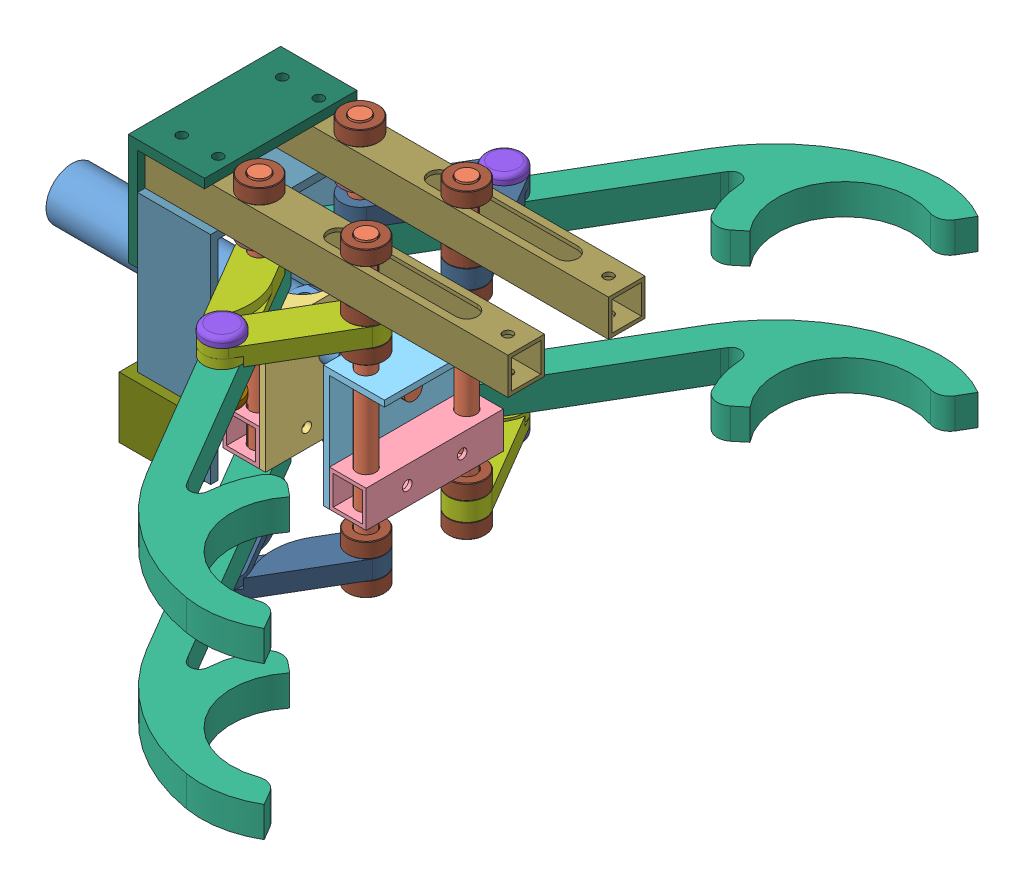
SolidWorks assembly hand_0302ue, configuration ﾃﾞﾌｫﾙﾄ. Lengths in mm.
Overall size (180.12 100 276.7).
52 component instances, 16 part files, 119 mates.
Components (placement in the parent):
- エアシリンダ_可動40-1: エアシリンダ_可動40 [ﾃﾞﾌｫﾙﾄ] at (65.512 -3.3304 50.561) x (1 0 0) z (0 1 0) size (112 17 17) (flexible)
  - ボディ_40-1: ボディ_40 [ﾃﾞﾌｫﾙﾄ] at (-67.4414 2.0168 92) size (92 17 17)
  - 軸_40-1: 軸_40 [ﾃﾞﾌｫﾙﾄ] at (-55.4414 2.0168 92) x (0 0.456107 -0.889925) z (1 0 0) size (6 6 100)
- l字-1: l字 [ﾃﾞﾌｫﾙﾄ] at (82.0707 63.6696 26.0442) x (0 0 1) z (-1 0 0) size (45 40 20)
- 偽l字-1: 偽l字 [ﾃﾞﾌｫﾙﾄ] at (82.0707 63.6696 71.0442) x (0 0 -1) z (1 0 0) size (45 12 12)
- l字改-1: l字改 [ﾃﾞﾌｫﾙﾄ] at (105.0707 63.6696 71.0442) x (0 0 -1) z (1 0 0) size (45 40 20)
- 偽l字-2: 偽l字 [ﾃﾞﾌｫﾙﾄ] at (117.0707 63.6696 71.0442) x (0 0 -1) z (1 0 0) size (45 12 12)
- 稲つかみ機構手 - コピー-1: 稲つかみ機構手 - コピー [ﾃﾞﾌｫﾙﾄ] at (114.8776 40.6696 140.8336) x (0.861801 0 -0.507246) z (0.507246 0 0.861801) size (42 10 148.45)
- 稲つかみ機構手 - コピー-2: 稲つかみ機構手 - コピー [ﾃﾞﾌｫﾙﾄ] at (114.8776 176.6696 -43.7451) x (0.861801 0 0.507246) z (0.507246 0 -0.861801) size (42 10 148.45)
- 稲つかみ機構手 - コピー-3: 稲つかみ機構手 - コピー [ﾃﾞﾌｫﾙﾄ] at (114.8776 -9.3304 140.8336) x (0.861801 0 -0.507246) z (0.507246 0 0.861801) size (42 10 148.45)
- 稲つかみ機構手 - コピー-4: 稲つかみ機構手 - コピー [ﾃﾞﾌｫﾙﾄ] at (114.8776 126.6696 -43.7451) x (0.861801 0 0.507246) z (0.507246 0 -0.861801) size (42 10 148.45)
- link-1: link [ﾃﾞﾌｫﾙﾄ] at (84.8207 113.6696 79.9103) x (0.507246 0 0.861801) z (-0.861801 0 0.507246) size (46.5 6 12)
- link-2: link [ﾃﾞﾌｫﾙﾄ] at (102.3207 119.6696 79.9103) x (-0.507246 0 0.861801) z (0.861801 0 0.507246) size (46.5 6 12)
- female-1: female [ﾃﾞﾌｫﾙﾄ] at (93.5707 122.6696 94.7764) x (-1 0 0) z (0 0 1) size (12 9 12)
- male-1: male [ﾃﾞﾌｫﾙﾄ] at (93.5707 100.6696 94.7764) size (12 18.8 12)
- link'-1: link' [ﾃﾞﾌｫﾙﾄ] at (84.8207 113.6696 17.1782) x (0.507246 0 -0.861801) z (0.861801 0 0.507246) size (46.5 6 12)
- link'-2: link' [ﾃﾞﾌｫﾙﾄ] at (102.3207 119.6696 17.1782) x (-0.507246 0 -0.861801) z (-0.861801 0 0.507246) size (46.5 6 12)
- female-2: female [ﾃﾞﾌｫﾙﾄ] at (93.5707 122.6696 2.3121) x (1 0 0) z (0 0 -1) size (12 9 12)
- male-2: male [ﾃﾞﾌｫﾙﾄ] at (93.5707 100.6696 2.3121) size (12 18.8 12)
- link-3: link [ﾃﾞﾌｫﾙﾄ] at (84.8207 53.6696 17.1782) x (0.507246 0 -0.861801) z (-0.861801 0 -0.507246) size (46.5 6 12)
- link-4: link [ﾃﾞﾌｫﾙﾄ] at (102.3207 47.6696 17.1782) x (-0.507246 0 -0.861801) z (0.861801 0 -0.507246) size (46.5 6 12)
- female-3: female [ﾃﾞﾌｫﾙﾄ] at (93.5707 44.6696 2.3121) size (12 9 12)
- male-3: male [ﾃﾞﾌｫﾙﾄ] at (93.5707 66.6696 2.3121) x (0.612505 0 -0.790466) z (-0.790466 0 -0.612505) size (12 18.8 12)
- link'-3: link' [ﾃﾞﾌｫﾙﾄ] at (84.8207 53.6696 79.9103) x (0.507246 0 0.861801) z (0.861801 0 -0.507246) size (46.5 6 12)
- link'-4: link' [ﾃﾞﾌｫﾙﾄ] at (102.3207 47.6696 79.9103) x (-0.507246 0 0.861801) z (-0.861801 0 -0.507246) size (46.5 6 12)
- female-4: female [ﾃﾞﾌｫﾙﾄ] at (93.5707 44.6696 94.7764) x (1 0 -0.000678) z (0.000678 0 1) size (12 9 12)
- male-4: male [ﾃﾞﾌｫﾙﾄ] at (93.5707 66.6696 94.7764) x (1 0 0) z (0 0 -1) size (12 18.8 12)
- セットカラー 内径6 外径12 厚さ5-1: セットカラー 内径6 外径12 厚さ5 [ﾃﾞﾌｫﾙﾄ] at (111.0707 58.6696 65.0442) x (0.999528 0 -0.030706) z (0 -1 0) size (12 12 5)
- セットカラー 内径6 外径12 厚さ5-2: セットカラー 内径6 外径12 厚さ5 [ﾃﾞﾌｫﾙﾄ] at (111.0707 53.6696 32.0442) x (-1 0 0) z (0 1 0) size (12 12 5)
- セットカラー 内径6 外径12 厚さ5-3: セットカラー 内径6 外径12 厚さ5 [ﾃﾞﾌｫﾙﾄ] at (111.0707 42.6696 65.0442) x (1 0 0) z (0 1 0) size (12 12 5)
- セットカラー 内径6 外径12 厚さ5-4: セットカラー 内径6 外径12 厚さ5 [ﾃﾞﾌｫﾙﾄ] at (111.0707 47.6696 32.0442) x (1 0 0) z (0 -1 0) size (12 12 5)
- セットカラー 内径6 外径12 厚さ5-5: セットカラー 内径6 外径12 厚さ5 [ﾃﾞﾌｫﾙﾄ] at (76.0707 47.6696 65.0442) x (1 0 0) z (0 -1 0) size (12 12 5)
- セットカラー 内径6 外径12 厚さ5-6: セットカラー 内径6 外径12 厚さ5 [ﾃﾞﾌｫﾙﾄ] at (76.0707 47.6696 32.0442) x (1 0 0) z (0 -1 0) size (12 12 5)
- セットカラー 内径6 外径12 厚さ5-7: セットカラー 内径6 外径12 厚さ5 [ﾃﾞﾌｫﾙﾄ] at (111.0707 113.6696 65.0442) x (1 0 0) z (0 -1 0) size (12 12 5)
- セットカラー 内径6 外径12 厚さ5-8: セットカラー 内径6 外径12 厚さ5 [ﾃﾞﾌｫﾙﾄ] at (111.0707 124.6696 65.0442) x (1 0 0) z (0 -1 0) size (12 12 5)
- セットカラー 内径6 外径12 厚さ5-9: セットカラー 内径6 外径12 厚さ5 [ﾃﾞﾌｫﾙﾄ] at (111.0707 113.6696 32.0442) x (1 0 0) z (0 -1 0) size (12 12 5)
- セットカラー 内径6 外径12 厚さ5-10: セットカラー 内径6 外径12 厚さ5 [ﾃﾞﾌｫﾙﾄ] at (111.0707 124.6696 32.0442) x (1 0 0) z (0 -1 0) size (12 12 5)
- 支え-1: 支え [ﾃﾞﾌｫﾙﾄ] at (13.5707 124.6696 71.0442) size (119 12 12)
- ブッシュ,内径６,外径８.1-1: ブッシュ,内径６,外径８.1 [ﾃﾞﾌｫﾙﾄ] at (80.1637 123.6696 63.0071) size (12 5.8 12)
- 支え-2: 支え [ﾃﾞﾌｫﾙﾄ] at (13.5707 124.6696 38.0442) size (119 12 12)
- ブッシュ,内径６,外径８.1-2: ブッシュ,内径６,外径８.1 [ﾃﾞﾌｫﾙﾄ] at (80.1637 123.6696 30.0071) size (12 5.8 12)
- 軸_40-1: 軸_40 [ﾃﾞﾌｫﾙﾄ] at (76.0707 142.1696 32.0442) x (1 0 0) z (0 -1 0) size (6 6 100)
- 軸_40-2: 軸_40 [ﾃﾞﾌｫﾙﾄ] at (76.0707 142.1696 65.0442) x (1 0 0) z (0 -1 0) size (6 6 100)
- 軸_40-3: 軸_40 [ﾃﾞﾌｫﾙﾄ] at (111.0707 142.1696 32.0442) x (-0.272872 0 0.96205) z (0 -1 0) size (6 6 100)
- 軸_40-4: 軸_40 [ﾃﾞﾌｫﾙﾄ] at (111.0707 142.1696 65.0442) x (1 0 0) z (0 -1 0) size (6 6 100)
- セットカラー 内径6 外径12 厚さ5-11: セットカラー 内径6 外径12 厚さ5 [ﾃﾞﾌｫﾙﾄ] at (76.0707 141.6696 32.0442) x (0.989147 0 -0.146932) z (0 -1 0) size (12 12 5)
- セットカラー 内径6 外径12 厚さ5-12: セットカラー 内径6 外径12 厚さ5 [ﾃﾞﾌｫﾙﾄ] at (76.0707 141.6696 65.0442) x (1 0 0) z (0 -1 0) size (12 12 5)
- セットカラー 内径6 外径12 厚さ5-13: セットカラー 内径6 外径12 厚さ5 [ﾃﾞﾌｫﾙﾄ] at (111.0707 141.6696 32.0442) x (1 0 0) z (0 -1 0) size (12 12 5)
- セットカラー 内径6 外径12 厚さ5-14: セットカラー 内径6 外径12 厚さ5 [ﾃﾞﾌｫﾙﾄ] at (111.0707 141.6696 65.0442) x (1 0 0) z (0 -1 0) size (12 12 5)
- 50×100角柱 24mm -1: 50×100角柱 24mm  [ﾃﾞﾌｫﾙﾄ] at (44.5707 74.6696 48.5442) x (0 0 -1) z (1 0 0) size (50 71 24)
- 25x36.5(50L字)x50＊2-1: 25x36.5(50L字)x50＊2 [ﾃﾞﾌｫﾙﾄ] at (41.5707 89.6696 23.5442) x (0 0 1) z (-1 0 0) size (50 36.5 25)
- Part3-1: Part3 [ﾃﾞﾌｫﾙﾄ] at (41.5707 53.6696 76.5442) x (0 1 0) z (-1 0 0) size (20 50 25)
Mates (geometry in assembly coordinates):
- 一致1: coincident anti-aligned: plane of エアシリンダ_可動40-1/ボディ_40-1 through (82.0707 88.6696 48.5442) normal (1 0 0); plane of l字-1 through (82.0707 101.6696 71.0442) normal (-1 0 0)
- 同心円1: concentric anti-aligned: circle of エアシリンダ_可動40-1/ボディ_40-1; circle of l字-1
- 平行1: parallel aligned: plane of エアシリンダ_可動40-1/ボディ_40-1 through (90.0707 97.1696 40.0442) normal (0 1 0); plane of l字-1 through (84.0707 103.6696 71.0442) normal (0 1 0)
- 一致4: coincident anti-aligned: plane of l字-1 through (82.0707 101.6696 71.0442) normal (-1 0 0); plane of 偽l字-1 through (82.0707 75.6696 26.0442) normal (1 0 0)
- 同心円2: concentric aligned: circle of l字-1; circle of 偽l字-1
- 同心円3: concentric aligned: circle of l字-1; circle of 偽l字-1
- 平行2: parallel aligned: plane of l字-1 through (84.0707 103.6696 71.0442) normal (0 1 0); plane of l字改-1 through (103.0707 103.6696 26.0442) normal (0 1 0)
- 同心円5: concentric aligned: circle of エアシリンダ_可動40-1/軸_40-1; circle of l字改-1
- 距離1: distance = 5 mm aligned: plane of l字改-1 through (105.0707 101.6696 26.0442) normal (1 0 0); plane of エアシリンダ_可動40-1/軸_40-1 through (110.0707 88.6696 48.5442) normal (1 0 0)
- 一致11: coincident anti-aligned: plane of l字改-1 through (105.0707 101.6696 26.0442) normal (1 0 0); plane of 偽l字-2 through (105.0707 75.6696 26.0442) normal (-1 0 0)
- 同心円6: concentric aligned: circle of l字改-1; circle of 偽l字-2
- 同心円7: concentric aligned: circle of l字改-1; circle of 偽l字-2
- 一致14: coincident anti-aligned: plane of l字-1 through (84.0707 103.6696 71.0442) normal (0 1 0); plane of 稲つかみ機構手 - コピー-1 through (156.6627 103.6696 169.5726) normal (0 -1 0)
- 同心円8: concentric anti-aligned: circle of l字-1; circle of 稲つかみ機構手 - コピー-1
- 一致16: coincident anti-aligned: plane of l字-1 through (84.0707 103.6696 71.0442) normal (0 1 0); plane of 稲つかみ機構手 - コピー-2 through (123.4956 103.6696 -38.6726) normal (0 -1 0)
- 同心円9: concentric aligned: circle of l字-1; circle of 稲つかみ機構手 - コピー-2
- 一致18: coincident anti-aligned: plane of 偽l字-1 through (82.0707 63.6696 26.0442) normal (0 -1 0); plane of 稲つかみ機構手 - コピー-3 through (123.4956 63.6696 135.7611) normal (0 1 0)
- 同心円10: concentric aligned: circle of 偽l字-1; circle of 稲つかみ機構手 - コピー-3
- 一致19: coincident anti-aligned: plane of 偽l字-1 through (82.0707 63.6696 26.0442) normal (0 -1 0); plane of 稲つかみ機構手 - コピー-4 through (156.6627 63.6696 -72.4841) normal (0 1 0)
- 同心円11: concentric anti-aligned: circle of 偽l字-1; circle of 稲つかみ機構手 - コピー-4
- 一致20: coincident anti-aligned: plane of 稲つかみ機構手 - コピー-1 through (123.4956 113.6696 135.7611) normal (0 1 0); plane of link-1 through (76.0707 113.6696 65.0442) normal (0 -1 0)
- 同心円12: concentric aligned: circle of 稲つかみ機構手 - コピー-1; circle of link-1
- 一致22: coincident aligned: plane of link-1 through (76.0707 113.6696 65.0442) normal (0 -1 0); plane of link-2 through (111.0707 113.6696 65.0442) normal (0 -1 0)
- 同心円13: concentric anti-aligned: circle of link-1; circle of link-2
- 同心円15: concentric aligned: circle of l字改-1; circle of link-2
- 一致26: coincident anti-aligned: plane of link-2 through (111.0707 119.6696 65.0442) normal (0 1 0); plane of female-1 through (93.5707 119.6696 94.7764) normal (0 -1 0)
- 同心円16: concentric aligned: circle of link-2; circle of female-1
- 一致27: coincident anti-aligned: cylinder of 稲つかみ機構手 - コピー-1; cylinder of male-1 through (93.5707 119.4696 94.7764) axis (0 -1 0) radius 3
- 一致28: coincident anti-aligned: plane of 稲つかみ機構手 - コピー-1 through (156.6627 103.6696 169.5726) normal (0 -1 0); plane of male-1 through (93.5707 103.6696 94.7764) normal (0 1 0)
- 同心円17: concentric anti-aligned: cylinder of female-1 through (93.5707 113.6696 94.7764) axis (0 1 0) radius 3.1; cylinder of male-1 through (93.5707 119.4696 94.7764) axis (0 -1 0) radius 3
- 一致29: coincident anti-aligned: plane of 稲つかみ機構手 - コピー-2 through (156.6627 113.6696 -72.4841) normal (0 1 0); plane of link'-1 through (76.0707 113.6696 32.0442) normal (0 -1 0)
- 一致30: coincident anti-aligned: circle of 稲つかみ機構手 - コピー-2; circle of link'-1
- 一致31: coincident aligned: plane of link'-1 through (76.0707 113.6696 32.0442) normal (0 -1 0); plane of link'-2 through (111.0707 113.6696 32.0442) normal (0 -1 0)
- 同心円18: concentric anti-aligned: circle of link'-1; circle of link'-2
- 同心円19: concentric aligned: circle of l字改-1; circle of link'-2
- 一致34: coincident anti-aligned: plane of link'-2 through (111.0707 119.6696 32.0442) normal (0 1 0); plane of female-2 through (93.5707 119.6696 2.3121) normal (0 -1 0)
- 同心円20: concentric aligned: circle of link'-2; circle of female-2
- 一致38: coincident anti-aligned: plane of 稲つかみ機構手 - コピー-2 through (123.4956 103.6696 -38.6726) normal (0 -1 0); plane of male-2 through (93.5707 103.6696 2.3121) normal (0 1 0)
- 同心円22: concentric anti-aligned: circle of 稲つかみ機構手 - コピー-2; circle of male-2
- 同心円23: concentric aligned: circle of 稲つかみ機構手 - コピー-4; circle of link-3
- 一致41: coincident anti-aligned: plane of 稲つかみ機構手 - コピー-4 through (123.4956 53.6696 -38.6726) normal (0 -1 0); plane of link-3 through (76.0707 53.6696 32.0442) normal (0 1 0)
- 一致42: coincident aligned: plane of link-3 through (76.0707 53.6696 32.0442) normal (0 1 0); plane of link-4 through (111.0707 53.6696 32.0442) normal (0 1 0)
- 同心円24: concentric aligned: circle of 偽l字-2; circle of link-4
- 同心円25: concentric aligned: cylinder of link-4 through (93.5707 53.6696 2.3121) axis (0 -1 0) radius 4.6; cylinder of female-3 through (93.5707 53.6696 2.3121) axis (0 -1 0) radius 4.5
- 一致43: coincident anti-aligned: plane of link-4 through (111.0707 47.6696 32.0442) normal (0 -1 0); plane of female-3 through (93.5707 47.6696 2.3121) normal (0 1 0)
- 同心円26: concentric anti-aligned: cylinder of link-3 through (93.5707 47.6696 2.3121) axis (0 1 0) radius 4.6; cylinder of female-3 through (93.5707 53.6696 2.3121) axis (0 -1 0) radius 4.5
- 同心円27: concentric anti-aligned: cylinder of female-2 through (93.5707 113.6696 2.3121) axis (0 1 0) radius 3.1; cylinder of male-2 through (93.5707 119.4696 2.3121) axis (0 -1 0) radius 3
- 同心円28: concentric anti-aligned: cylinder of female-3 through (93.5707 53.6696 2.3121) axis (0 -1 0) radius 3.1; cylinder of male-3 through (93.5707 47.8696 2.3121) axis (0 1 0) radius 3
- 同心円29: concentric anti-aligned: cylinder of 稲つかみ機構手 - コピー-4 through (93.5707 126.6696 2.3121) axis (0 -1 0) radius 3; cylinder of male-3 through (93.5707 47.8696 2.3121) axis (0 1 0) radius 3
- 一致44: coincident anti-aligned: plane of 稲つかみ機構手 - コピー-4 through (156.6627 63.6696 -72.4841) normal (0 1 0); plane of male-3 through (93.5707 63.6696 2.3121) normal (0 -1 0)
- 一致45: coincident anti-aligned: plane of 稲つかみ機構手 - コピー-3 through (156.6627 53.6696 169.5726) normal (0 -1 0); plane of link'-3 through (76.0707 53.6696 65.0442) normal (0 1 0)
- 同心円30: concentric anti-aligned: circle of 稲つかみ機構手 - コピー-3; circle of link'-3
- 同心円31: concentric anti-aligned: circle of 偽l字-2; cylinder of link'-4 through (111.0707 53.6696 65.0442) axis (0 -1 0) radius 3
- 一致48: coincident aligned: plane of link'-3 through (76.0707 53.6696 65.0442) normal (0 1 0); plane of link'-4 through (111.0707 53.6696 65.0442) normal (0 1 0)
- 同心円32: concentric aligned: cylinder of link'-4 through (93.5707 53.6696 94.7764) axis (0 -1 0) radius 4.6; cylinder of female-4 through (93.5707 53.6696 94.7764) axis (0 -1 0) radius 4.5
- 一致49: coincident anti-aligned: plane of link'-4 through (111.0707 47.6696 65.0442) normal (0 -1 0); plane of female-4 through (93.5707 47.6696 94.7764) normal (0 1 0)
- 同心円33: concentric anti-aligned: cylinder of link'-3 through (93.5707 47.6696 94.7764) axis (0 1 0) radius 4.6; cylinder of female-4 through (93.5707 53.6696 94.7764) axis (0 -1 0) radius 4.5
- 同心円34: concentric anti-aligned: cylinder of female-4 through (93.5707 53.6696 94.7764) axis (0 -1 0) radius 3.1; cylinder of male-4 through (93.5707 47.8696 94.7764) axis (0 1 0) radius 3
- 一致51: coincident anti-aligned: plane of 稲つかみ機構手 - コピー-3 through (123.4956 63.6696 135.7611) normal (0 1 0); plane of male-4 through (93.5707 63.6696 94.7764) normal (0 -1 0)
- 同心円35: concentric aligned: cylinder of 稲つかみ機構手 - コピー-3 through (93.5707 -9.3304 94.7764) axis (0 1 0) radius 3; cylinder of male-4 through (93.5707 47.8696 94.7764) axis (0 1 0) radius 3
- 一致52: coincident anti-aligned: plane of link'-4 through (111.0707 53.6696 65.0442) normal (0 1 0); plane of セットカラー 内径6 外径12 厚さ5-1 through (111.0707 53.6696 65.0442) normal (0 -1 0)
- 同心円36: concentric aligned: circle of link'-4; cylinder of セットカラー 内径6 外径12 厚さ5-1 through (111.0707 53.6696 65.0442) axis (0 1 0) radius 3
- 一致54: coincident anti-aligned: plane of link-4 through (111.0707 53.6696 32.0442) normal (0 1 0); plane of セットカラー 内径6 外径12 厚さ5-2 through (111.0707 53.6696 32.0442) normal (0 -1 0)
- 同心円37: concentric aligned: cylinder of セットカラー 内径6 外径12 厚さ5-2 through (111.0707 58.6696 32.0442) axis (0 -1 0) radius 3; cylinder of link-4 through (111.0707 53.6696 32.0442) axis (0 -1 0) radius 3
- 一致56: coincident anti-aligned: plane of link'-4 through (111.0707 47.6696 65.0442) normal (0 -1 0); plane of セットカラー 内径6 外径12 厚さ5-3 through (111.0707 47.6696 65.0442) normal (0 1 0)
- 同心円38: concentric aligned: cylinder of link'-4 through (111.0707 53.6696 65.0442) axis (0 -1 0) radius 3; cylinder of セットカラー 内径6 外径12 厚さ5-3 through (111.0707 47.6696 65.0442) axis (0 -1 0) radius 3
- 一致57: coincident anti-aligned: plane of link-4 through (111.0707 47.6696 32.0442) normal (0 -1 0); plane of セットカラー 内径6 外径12 厚さ5-4 through (111.0707 47.6696 32.0442) normal (0 1 0)
- 同心円39: concentric anti-aligned: cylinder of link-4 through (111.0707 53.6696 32.0442) axis (0 -1 0) radius 3; cylinder of セットカラー 内径6 外径12 厚さ5-4 through (111.0707 42.6696 32.0442) axis (0 1 0) radius 3
- 一致58: coincident anti-aligned: plane of link'-3 through (76.0707 47.6696 65.0442) normal (0 -1 0); plane of セットカラー 内径6 外径12 厚さ5-5 through (76.0707 47.6696 65.0442) normal (0 1 0)
- 同心円40: concentric aligned: cylinder of link'-3 through (76.0707 47.6696 65.0442) axis (0 1 0) radius 3; cylinder of セットカラー 内径6 外径12 厚さ5-5 through (76.0707 42.6696 65.0442) axis (0 1 0) radius 3
- 一致59: coincident anti-aligned: plane of link-3 through (76.0707 47.6696 32.0442) normal (0 -1 0); plane of セットカラー 内径6 外径12 厚さ5-6 through (76.0707 47.6696 32.0442) normal (0 1 0)
- 同心円41: concentric aligned: cylinder of link-3 through (76.0707 47.6696 32.0442) axis (0 1 0) radius 3; cylinder of セットカラー 内径6 外径12 厚さ5-6 through (76.0707 42.6696 32.0442) axis (0 1 0) radius 3
- 一致60: coincident anti-aligned: plane of link-2 through (111.0707 113.6696 65.0442) normal (0 -1 0); plane of セットカラー 内径6 外径12 厚さ5-7 through (111.0707 113.6696 65.0442) normal (0 1 0)
- 同心円42: concentric aligned: cylinder of link-2 through (111.0707 113.6696 65.0442) axis (0 1 0) radius 3; cylinder of セットカラー 内径6 外径12 厚さ5-7 through (111.0707 108.6696 65.0442) axis (0 1 0) radius 3
- 一致61: coincident anti-aligned: plane of link-2 through (111.0707 119.6696 65.0442) normal (0 1 0); plane of セットカラー 内径6 外径12 厚さ5-8 through (111.0707 119.6696 65.0442) normal (0 -1 0)
- 同心円43: concentric aligned: cylinder of セットカラー 内径6 外径12 厚さ5-8 through (111.0707 119.6696 65.0442) axis (0 1 0) radius 3; cylinder of link-2 through (111.0707 113.6696 65.0442) axis (0 1 0) radius 3
- 一致62: coincident anti-aligned: plane of link'-2 through (111.0707 113.6696 32.0442) normal (0 -1 0); plane of セットカラー 内径6 外径12 厚さ5-9 through (111.0707 113.6696 32.0442) normal (0 1 0)
- 同心円44: concentric aligned: cylinder of link'-2 through (111.0707 113.6696 32.0442) axis (0 1 0) radius 3; cylinder of セットカラー 内径6 外径12 厚さ5-9 through (111.0707 108.6696 32.0442) axis (0 1 0) radius 3
- 一致63: coincident anti-aligned: plane of link'-2 through (111.0707 119.6696 32.0442) normal (0 1 0); plane of セットカラー 内径6 外径12 厚さ5-10 through (111.0707 119.6696 32.0442) normal (0 -1 0)
- 同心円45: concentric aligned: cylinder of link'-2 through (111.0707 113.6696 32.0442) axis (0 1 0) radius 3; cylinder of セットカラー 内径6 外径12 厚さ5-10 through (111.0707 119.6696 32.0442) axis (0 1 0) radius 3
- 一致64: coincident anti-aligned: plane of セットカラー 内径6 外径12 厚さ5-8 through (111.0707 124.6696 65.0442) normal (0 1 0); plane of 支え-1 through (163.5707 124.6696 71.0442) normal (0 -1 0)
- 一致65: coincident anti-aligned: plane of 支え-1 through (163.5707 124.6696 71.0442) normal (0 -1 0); plane of ブッシュ,内径６,外径８.1-1 through (76.0707 124.6696 65.0442) normal (0 1 0)
- 同心円46: concentric anti-aligned: cylinder of 支え-1 through (76.0707 124.6696 65.0442) axis (0 1 0) radius 4.05; cylinder of ブッシュ,内径６,外径８.1-1 through (76.0707 129.4696 65.0442) axis (0 -1 0) radius 4.05
- 同心円47: concentric aligned: cylinder of link-1 through (76.0707 119.6696 65.0442) axis (0 -1 0) radius 3; cylinder of ブッシュ,内径６,外径８.1-1 through (76.0707 129.4696 65.0442) axis (0 -1 0) radius 3.05
- 平行3: parallel aligned: plane of エアシリンダ_可動40-1/ボディ_40-1 through (90.0707 80.1696 57.0442) normal (0 0 1); plane of 支え-1 through (163.5707 136.6696 71.0442) normal (0 0 1)
- 一致67: coincident anti-aligned: plane of セットカラー 内径6 外径12 厚さ5-10 through (111.0707 124.6696 32.0442) normal (0 1 0); plane of 支え-2 through (163.5707 124.6696 38.0442) normal (0 -1 0)
- 平行4: parallel aligned: plane of エアシリンダ_可動40-1/ボディ_40-1 through (90.0707 80.1696 40.0442) normal (0 0 -1); plane of 支え-2 through (163.5707 136.6696 26.0442) normal (0 0 -1)
- 一致69: coincident anti-aligned: plane of 支え-2 through (163.5707 124.6696 38.0442) normal (0 -1 0); plane of ブッシュ,内径６,外径８.1-2 through (76.0707 124.6696 32.0442) normal (0 1 0)
- 同心円48: concentric anti-aligned: cylinder of 支え-2 through (76.0707 124.6696 32.0442) axis (0 1 0) radius 4.05; cylinder of ブッシュ,内径６,外径８.1-2 through (76.0707 129.4696 32.0442) axis (0 -1 0) radius 4.05
- 同心円49: concentric aligned: cylinder of link'-1 through (76.0707 119.6696 32.0442) axis (0 -1 0) radius 3; cylinder of ブッシュ,内径６,外径８.1-2 through (76.0707 129.4696 32.0442) axis (0 -1 0) radius 3.05
- 同心円50: concentric aligned: cylinder of セットカラー 内径6 外径12 厚さ5-6 through (76.0707 42.6696 32.0442) axis (0 1 0) radius 3; cylinder of 軸_40-1 through (76.0707 42.1696 32.0442) axis (0 1 0) radius 3
- 同心円51: concentric aligned: cylinder of セットカラー 内径6 外径12 厚さ5-5 through (76.0707 42.6696 65.0442) axis (0 1 0) radius 3; cylinder of 軸_40-2 through (76.0707 42.1696 65.0442) axis (0 1 0) radius 3
- 同心円52: concentric aligned: cylinder of セットカラー 内径6 外径12 厚さ5-4 through (111.0707 42.6696 32.0442) axis (0 1 0) radius 3; cylinder of 軸_40-3 through (111.0707 42.1696 32.0442) axis (0 1 0) radius 3
- 同心円53: concentric anti-aligned: cylinder of セットカラー 内径6 外径12 厚さ5-3 through (111.0707 47.6696 65.0442) axis (0 -1 0) radius 3; cylinder of 軸_40-4 through (111.0707 42.1696 65.0442) axis (0 1 0) radius 3
- 同心円54: concentric aligned: cylinder of 軸_40-1 through (76.0707 42.1696 32.0442) axis (0 1 0) radius 3; cylinder of セットカラー 内径6 外径12 厚さ5-11 through (76.0707 136.6696 32.0442) axis (0 1 0) radius 3
- 一致74: coincident anti-aligned: plane of 支え-2 through (163.5707 136.6696 38.0442) normal (0 1 0); plane of セットカラー 内径6 外径12 厚さ5-11 through (76.0707 136.6696 32.0442) normal (0 -1 0)
- 距離2: distance = 0.5 mm aligned: plane of セットカラー 内径6 外径12 厚さ5-6 through (76.0707 42.6696 32.0442) normal (0 -1 0); plane of 軸_40-1 through (76.0707 42.1696 32.0442) normal (0 -1 0)
- 距離3: distance = 0.5 mm aligned: plane of セットカラー 内径6 外径12 厚さ5-5 through (76.0707 42.6696 65.0442) normal (0 -1 0); plane of 軸_40-2 through (76.0707 42.1696 65.0442) normal (0 -1 0)
- 距離4: distance = 0.5 mm aligned: plane of セットカラー 内径6 外径12 厚さ5-4 through (111.0707 42.6696 32.0442) normal (0 -1 0); plane of 軸_40-3 through (111.0707 42.1696 32.0442) normal (0 -1 0)
- 距離5: distance = 0.5 mm aligned: plane of セットカラー 内径6 外径12 厚さ5-3 through (111.0707 42.6696 65.0442) normal (0 -1 0); plane of 軸_40-4 through (111.0707 42.1696 65.0442) normal (0 -1 0)
- 一致75: coincident anti-aligned: plane of 支え-1 through (163.5707 136.6696 71.0442) normal (0 1 0); plane of セットカラー 内径6 外径12 厚さ5-12 through (76.0707 136.6696 65.0442) normal (0 -1 0)
- 同心円55: concentric aligned: cylinder of 軸_40-2 through (76.0707 42.1696 65.0442) axis (0 1 0) radius 3; cylinder of セットカラー 内径6 外径12 厚さ5-12 through (76.0707 136.6696 65.0442) axis (0 1 0) radius 3
- 一致76: coincident anti-aligned: plane of 支え-2 through (163.5707 136.6696 38.0442) normal (0 1 0); plane of セットカラー 内径6 外径12 厚さ5-13 through (111.0707 136.6696 32.0442) normal (0 -1 0)
- 同心円56: concentric aligned: cylinder of 軸_40-3 through (111.0707 42.1696 32.0442) axis (0 1 0) radius 3; cylinder of セットカラー 内径6 外径12 厚さ5-13 through (111.0707 136.6696 32.0442) axis (0 1 0) radius 3
- 一致77: coincident anti-aligned: plane of 支え-1 through (163.5707 136.6696 71.0442) normal (0 1 0); plane of セットカラー 内径6 外径12 厚さ5-14 through (111.0707 136.6696 65.0442) normal (0 -1 0)
- 同心円57: concentric aligned: cylinder of 軸_40-4 through (111.0707 42.1696 65.0442) axis (0 1 0) radius 3; cylinder of セットカラー 内径6 外径12 厚さ5-14 through (111.0707 136.6696 65.0442) axis (0 1 0) radius 3
- 一致78: coincident aligned: plane of 支え-2 through (44.5707 124.6696 38.0442) normal (-1 0 0); plane of 50×100角柱 24mm -1 through (44.5707 74.6696 48.5442) normal (-1 0 0)
- 同心円58: concentric anti-aligned: circle of 支え-2; circle of 50×100角柱 24mm -1
- 同心円59: concentric anti-aligned: circle of 支え-1; circle of 50×100角柱 24mm -1
- 一致82: coincident anti-aligned: plane of 支え-2 through (163.5707 124.6696 38.0442) normal (0 -1 0); plane of 50×100角柱 24mm -1 through (68.5707 124.6696 73.5442) normal (0 1 0)
- 一致83: coincident anti-aligned: plane of 50×100角柱 24mm -1 through (68.5707 24.6696 73.5442) normal (0 -1 0); plane of 25x50L字x50-1 through (66.5707 24.6696 23.5442) normal (0 1 0)
- 同心円60: concentric aligned: circle of 50×100角柱 24mm -1; circle of 25x50L字-1
- 同心円61: concentric aligned: circle of 50×100角柱 24mm -1; circle of 25x50L字-1
- 一致86: coincident anti-aligned: plane of 支え-1 through (163.5707 136.6696 71.0442) normal (0 1 0); plane of 25x36.5(50L字)x50-1 through (66.5707 136.6696 73.5442) normal (0 -1 0)
- 同心円62: concentric anti-aligned: circle of 支え-1; cylinder of 25x36.5(50L字)x50-1 through (62.5707 139.6696 65.0442) axis (0 -1 0) radius 1.6
- 同心円63: concentric anti-aligned: cylinder of 支え-2 through (50.5707 124.6696 32.0442) axis (0 1 0) radius 1.6; circle of 25x50L字_36.5-1
- 一致87: coincident anti-aligned: plane of 50×100角柱 24mm -1 through (68.5707 124.6696 73.5442) normal (0 0 1); plane of Part3-1 through (41.5707 73.6696 73.5442) normal (0 0 -1)
- 一致88: coincident anti-aligned: plane of 50×100角柱 24mm -1 through (44.5707 74.6696 48.5442) normal (-1 0 0); plane of Part3-1 through (44.5707 73.6696 76.5442) normal (1 0 0)
- 一致89: coincident aligned: plane of 50×100角柱 24mm -1 through (44.5707 53.6696 48.5442) normal (0 -1 0); plane of Part3-1 through (41.5707 53.6696 76.5442) normal (0 -1 0)
